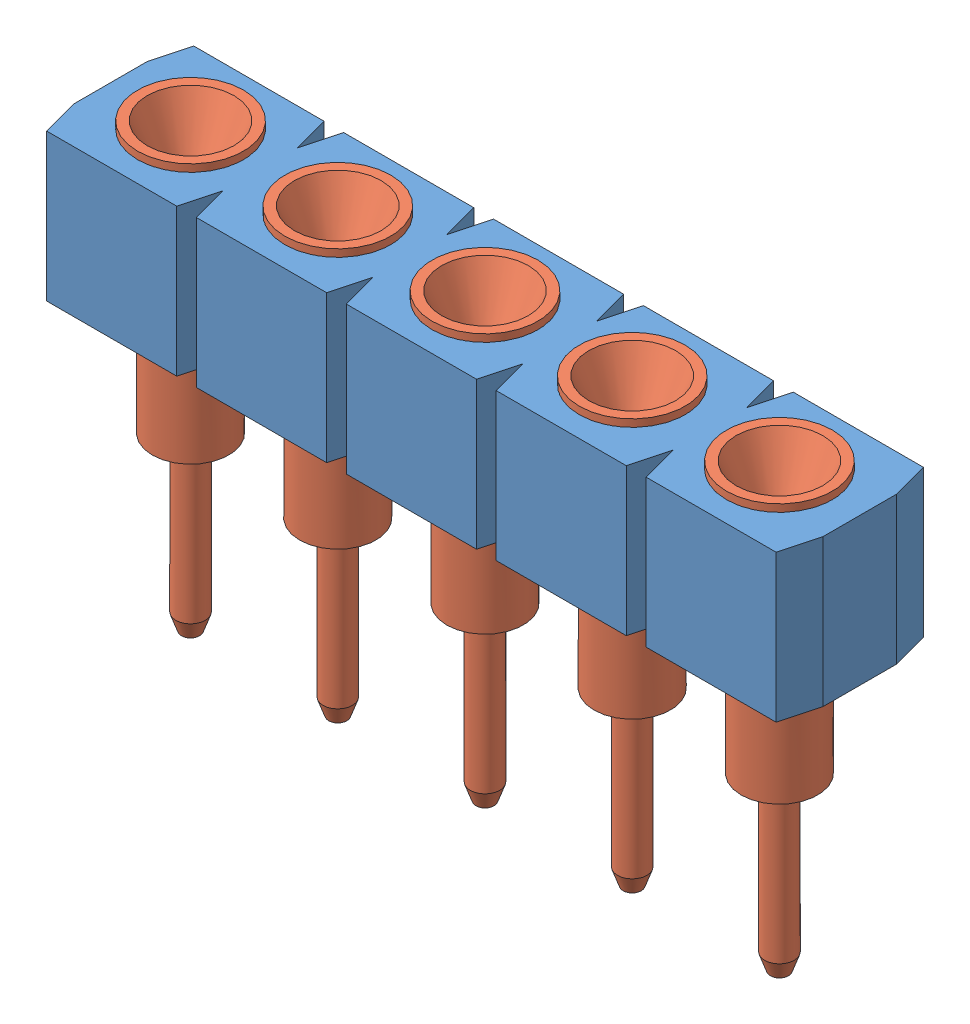
SolidWorks assembly SS-105-G-2, configuration Default. Lengths in mm.
Overall size (12.93 7.62 2.54).
6 component instances, 2 part files, 0 mates.
Components (placement in the parent):
- _SS-105-G-2_socket-1: _SS-105-G-2_socket [Default] at (-6.4643 0 0) size (12.93 2.54 2.54)
- _SS-105-G-2_pins-1: _SS-105-G-2_pins [Default] at (-5.08 2.54 0) size (1.83 7.62 1.83)
- _SS-105-G-2_pins-2: _SS-105-G-2_pins [Default] at (-2.54 2.54 0) size (1.83 7.62 1.83)
- _SS-105-G-2_pins-3: _SS-105-G-2_pins [Default] at (0 2.54 0) size (1.83 7.62 1.83)
- _SS-105-G-2_pins-4: _SS-105-G-2_pins [Default] at (2.54 2.54 0) size (1.83 7.62 1.83)
- _SS-105-G-2_pins-5: _SS-105-G-2_pins [Default] at (5.08 2.54 0) size (1.83 7.62 1.83)
